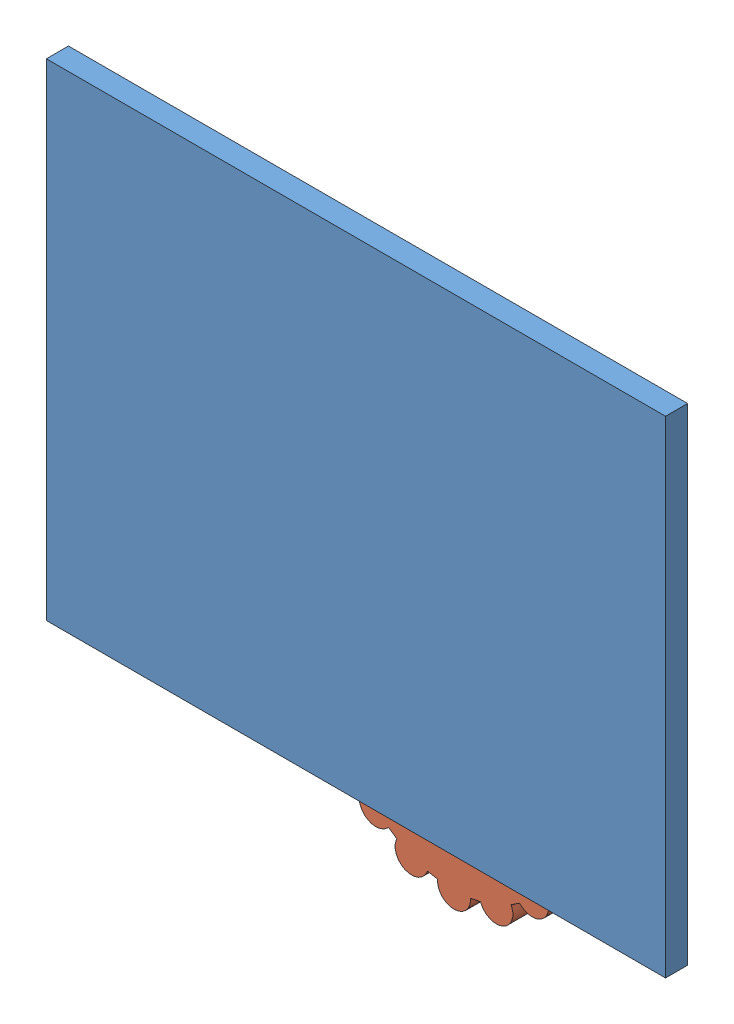
SolidWorks assembly Test_6_Working, configuration Default. Lengths in mm.
Overall size (280 250.91 20).
3 component instances, 3 part files, 7 mates.
Components (placement in the parent):
- Background-1: Background [Default] at (-164.4985 122.0365 0) size (280 220 10)
- Gear_3-2: Gear_3 [Default] at (-105.6577 26.5914 -10) size (115 115 10)
- Gear_3-3: Gear_3 [Default] at (-213.1724 71.5073 -10) size (115 115 10)
Mates (geometry in assembly coordinates):
- Coincident3: coincident anti-aligned: plane of Background-1 through (-164.4985 122.0365 0) normal (0 0 -1)
- Coincident4: coincident aligned: plane of Background-1 through (0 220 10) normal (1 0 0)
- Coincident5: coincident anti-aligned: plane of Background-1 through (-280 0 10) normal (0 -1 0)
- Concentric1: concentric anti-aligned: circle of Gear_3-2
- Coincident10: coincident anti-aligned: plane of Background-1 through (-164.4985 122.0365 0) normal (0 0 -1); plane of Gear_3-2 through (-105.6577 26.5914 0) normal (0 0 1)
- Concentric2: concentric anti-aligned: circle of Gear_3-3
- Coincident11: coincident anti-aligned: plane of Background-1 through (-164.4985 122.0365 0) normal (0 0 -1); plane of Gear_3-3 through (-213.1724 71.5073 0) normal (0 0 1)
